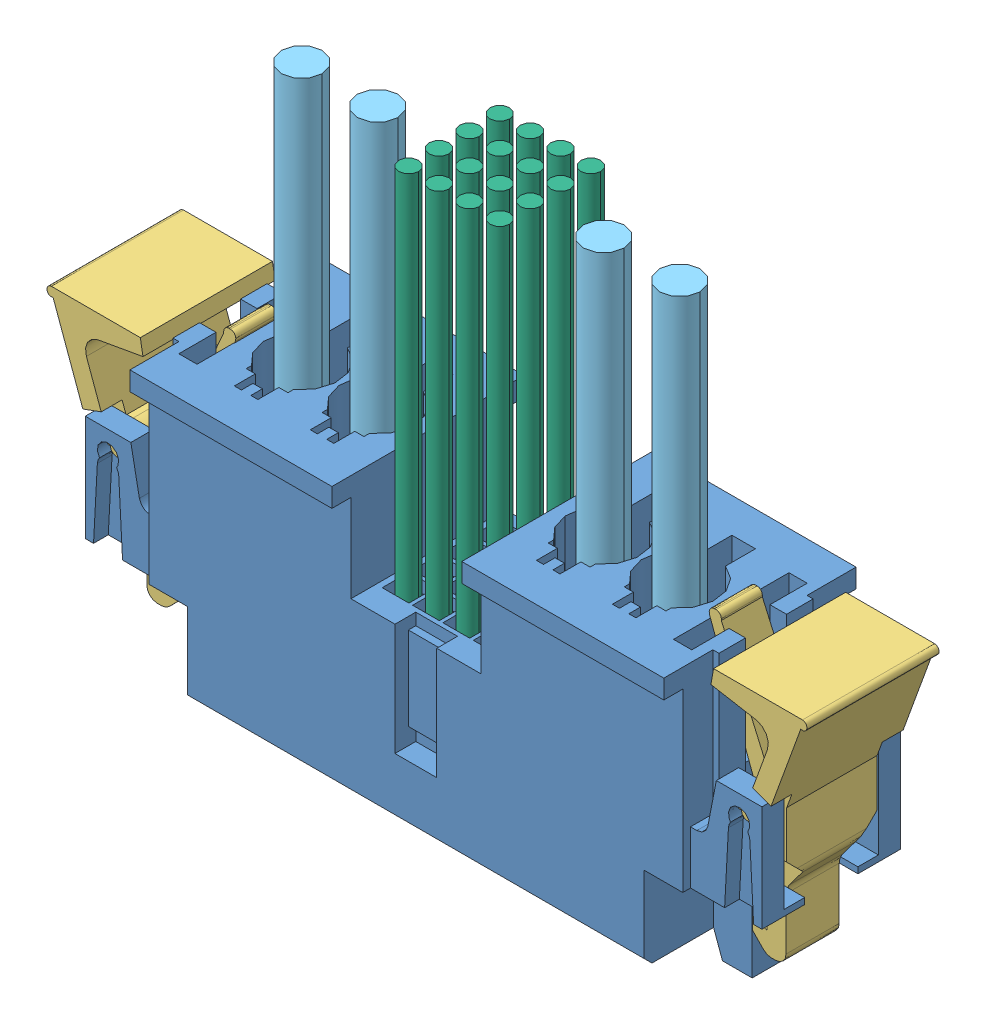
SolidWorks assembly Assem4, configuration Default. Lengths in mm.
Overall size (50.05 37.93 12.66).
24 component instances, 10 part files, 3 mates.
Components (placement in the parent):
- MPTC-02-16-02-6.30-01-L-V-LC-1: MPTC-02-16-02-6.30-01-L-V-LC [Default] at origin size (39.44 14.43 12.45) (suppressed, hidden)
  - MPTC_02_16_02_6_30_01_L_V_LC-1: MPTC_02_16_02_6_30_01_L_V_LC [Default] at (0 5.69 0) x (1 0 0) z (0 1 0) size (39.44 12.45 14.43)
    - _MPTC_02_16_02_6_30_V_LC_t_2-1: _MPTC_02_16_02_6_30_V_LC_t_2 [Default] at origin size (39.44 12.45 11.38)
    - _MPTC_02_16_02_6_30_01_V_p_4-1: _MPTC_02_16_02_6_30_01_V_p_4 [Default] at (0 0.0048 0.532) size (6.5 6.5 13.69)
    - _MPTC_01_04_01_6_30_01_L_V_c_6-1: _MPTC_01_04_01_6_30_01_L_V_c_6 [Default] at (16.255 -2.145 -4.76) x (0 1 0) z (1 0 0) size (1.42 4.7 0.25)
    - _MPTC_01_04_01_6_30_01_L_V_c_6-2: _MPTC_01_04_01_6_30_01_L_V_c_6 [Default] at (-16.255 -2.145 -4.76) x (0 1 0) z (1 0 0) size (1.42 4.7 0.25)
    - _MPTC_01_V_pp_9-1: _MPTC_01_V_pp_9 [Default] at (12.445 -2.605 -1.744) x (0 0 1) z (-1 0 0) size (13.75 7.62 2.29)
    - _MPTC_01_V_pp_9-2: _MPTC_01_V_pp_9 [Default] at (-12.445 -2.605 -1.744) x (0 0 1) z (-1 0 0) size (13.75 7.62 2.29)
    - _MPTC_01_V_pp_9-3: _MPTC_01_V_pp_9 [Default] at (7.445 -2.605 -1.744) x (0 0 1) z (-1 0 0) size (13.75 7.62 2.29)
    - _MPTC_01_V_pp_9-4: _MPTC_01_V_pp_9 [Default] at (-7.445 -2.605 -1.744) x (0 0 1) z (-1 0 0) size (13.75 7.62 2.29)
- MPCC_2_16_2_L_46_80_00_S-1: MPCC_2_16_2_L_46_80_00_S [Default] at (0 24.7 0) x (0 1 0) z (-1 0 0) size (37.93 12.66 50.05)
  - _MPC_2_16_2_C_body_2-1: _MPC_2_16_2_C_body_2 [Default] at (0 -6.33 0) x (0 0 1) z (-1 0 0) size (44.55 12.66 20.9)
  - _MPC_16__V_signal_pins_4-1: _MPC_16__V_signal_pins_4 [Default] at (-16.28 0 0) x (0 0 1) z (-1 0 0) size (7.32 6.5 10.38)
  - _LTC_22_6-1: _LTC_22_6 [Default] at (-7.3 0 20.775) x (0 -1 0) z (0 0 -1) size (8.7 17.64 9.44)
  - _LTC_22_6-2: _LTC_22_6 [Default] at (-7.3 0 -20.775) x (0 1 0) z (0 0 1) size (8.7 17.64 9.44)
  - _MPC_01_V_pp_9-1: _MPC_01_V_pp_9 [Default] at (-15.85 -2.54 -12.445) x (-1 0 0) z (0 0 -1) size (9.41 7.05 3)
  - _MPC_01_V_pp_9-2: _MPC_01_V_pp_9 [Default] at (-15.85 -2.54 -7.445) x (-1 0 0) z (0 0 -1) size (9.41 7.05 3)
  - _MPC_01_V_pp_9-3: _MPC_01_V_pp_9 [Default] at (-15.85 -2.54 7.445) x (-1 0 0) z (0 0 -1) size (9.41 7.05 3)
  - _MPC_01_V_pp_9-4: _MPC_01_V_pp_9 [Default] at (-15.85 -2.54 12.445) x (-1 0 0) z (0 0 -1) size (9.41 7.05 3)
  - _DWC_14_1_14-1: _DWC_14_1_14 [Default] at (-7.97 -0.15 12.445) x (0 0 1) z (-1 0 0) size (2.67 2.67 25)
  - _DWC_14_1_14-2: _DWC_14_1_14 [Default] at (-7.97 -0.15 7.445) x (0 0 1) z (-1 0 0) size (2.67 2.67 25)
  - _DWC_14_1_14-3: _DWC_14_1_14 [Default] at (-7.97 -0.15 -7.445) x (0 0 1) z (-1 0 0) size (2.67 2.67 25)
  - _DWC_14_1_14-4: _DWC_14_1_14 [Default] at (-7.97 -0.15 -12.445) x (0 0 1) z (-1 0 0) size (2.67 2.67 25)
  - _DWC_26_16_19-1: _DWC_26_16_19 [Default] at (-8.97 -2.555 0) x (0 0 1) z (-1 0 0) size (8 8 26)
Mates (geometry in assembly coordinates):
- Width1: width: plane of MPTC-02-16-02-6.30-01-L-V-LC-1/MPTC_02_16_02_6_30_01_L_V_LC-1/_MPTC_02_16_02_6_30_V_LC_t_2-1 through (15.291 6.3 -5.336) normal (0 0 1); plane of MPTC-02-16-02-6.30-01-L-V-LC-1/MPTC_02_16_02_6_30_01_L_V_LC-1/_MPTC_02_16_02_6_30_V_LC_t_2-1 through (-15.291 6.3 5.336) normal (0 0 -1); plane of MPCC_2_16_2_L_46_80_00_S-1/_MPC_2_16_2_C_body_2-1 through (-17.575 23.45 -5.08) normal (0 0 -1); plane of MPCC_2_16_2_L_46_80_00_S-1/_MPC_2_16_2_C_body_2-1 through (17.575 23.45 5.08) normal (0 0 1)
- Width2: width: plane of MPCC_2_16_2_L_46_80_00_S-1/_MPC_2_16_2_C_body_2-1 through (-17.575 15.015 6.33) normal (-1 0 0); plane of MPCC_2_16_2_L_46_80_00_S-1/_MPC_2_16_2_C_body_2-1 through (17.575 15.015 -6.33) normal (1 0 0); plane of MPTC-02-16-02-6.30-01-L-V-LC-1/MPTC_02_16_02_6_30_01_L_V_LC-1/_MPTC_02_16_02_6_30_V_LC_t_2-1 through (-17.831 11.38 -4.824) normal (1 0 0); plane of MPTC-02-16-02-6.30-01-L-V-LC-1/MPTC_02_16_02_6_30_01_L_V_LC-1/_MPTC_02_16_02_6_30_V_LC_t_2-1 through (17.831 11.38 0.764) normal (-1 0 0)
- Coincident1: coincident: plane of MPTC-02-16-02-6.30-01-L-V-LC-1/MPTC_02_16_02_6_30_01_L_V_LC-1/_MPTC_02_16_02_6_30_V_LC_t_2-1 through (0 6.3 0) normal (0 1 0); plane of MPCC_2_16_2_L_46_80_00_S-1/_MPC_2_16_2_C_body_2-1 through (15.035 6.3 -6.33) normal (0 -1 0)
